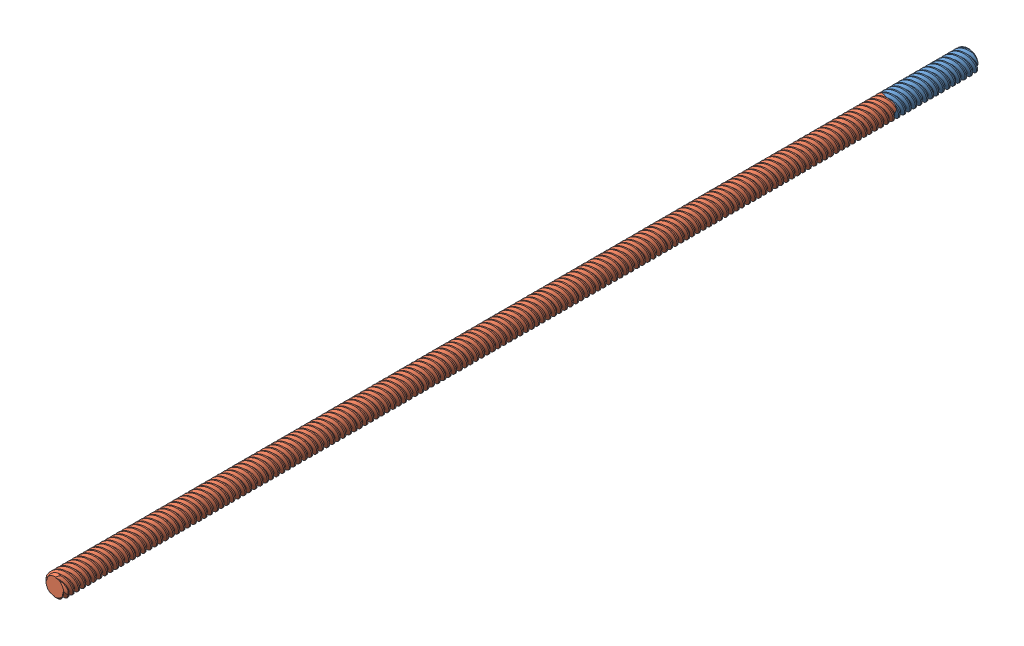
SolidWorks assembly Assem2, configuration Default. Lengths in mm.
Overall size (11.33 11.33 330.49).
2 component instances, 2 part files, 1 mates.
Components (placement in the parent):
- 634050-8mm 30mm acme-1: 634050-8mm 30mm acme [Default] at (8.6798 16.9055 161.5487) size (8.26 8.26 30.48)
- 634050-8mm 300mm acme-1: 634050-8mm 300mm acme [Default] at (8.6798 16.9055 186.7487) x (0.515038 0.857167 0) z (0 0 -1) size (8.26 8.26 300.48)
Mates (geometry in assembly coordinates):
- Lock2: lock: unknown of 634050-8mm 30mm acme-1; unknown of 634050-8mm 300mm acme-1
